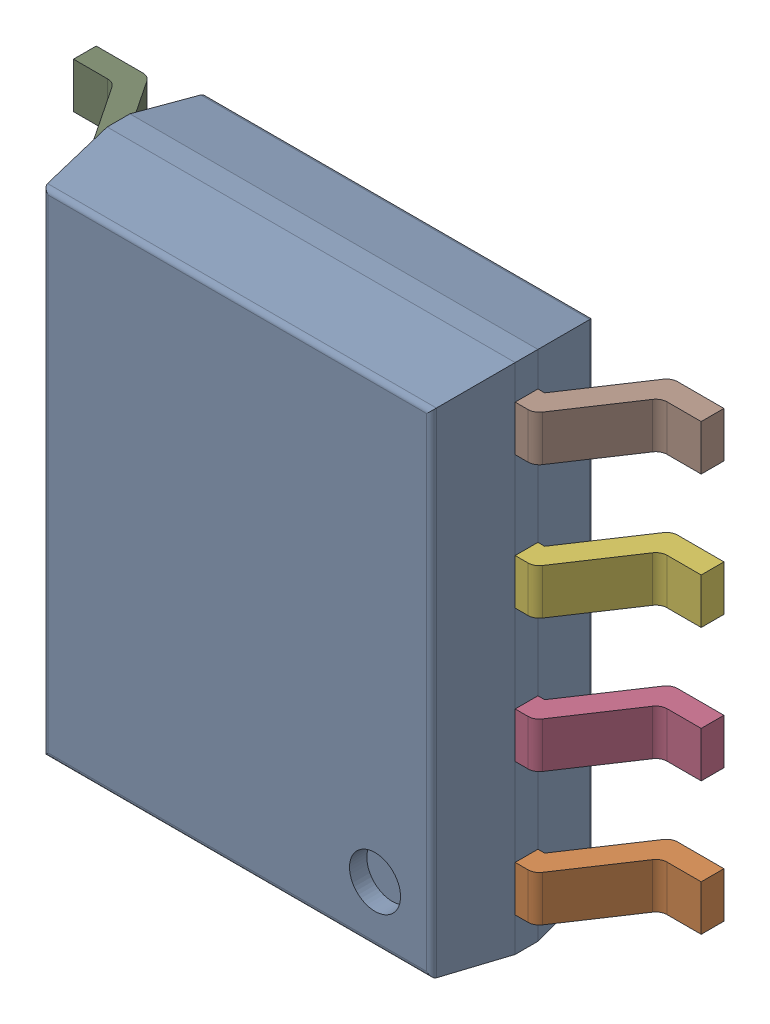
SolidWorks assembly IC23_1.step, configuration Default. Lengths in mm.
Overall size (6 4.9 1.65).
4 component instances, 3 part files, 0 mates.
Components (placement in the parent):
- 6348795168_1.step-3: 6348795168_1.step [Default] at (530.978 330.454 0) x (-1 0 0) z (0 0 1) size (6 4.9 1.65)
  - Body-6_1.step-3: Body-6_1.step [Default] at origin size (3.9 4.9 1.55)
  - PinsArrayLR_1.step-3: PinsArrayLR_1.step [Default] at origin size (6 4.24 0.95)
  - ThermalPad_1.step-3: ThermalPad_1.step [Default] at (-1.045 -1.045 0) size (2.09 2.09 0.1)
